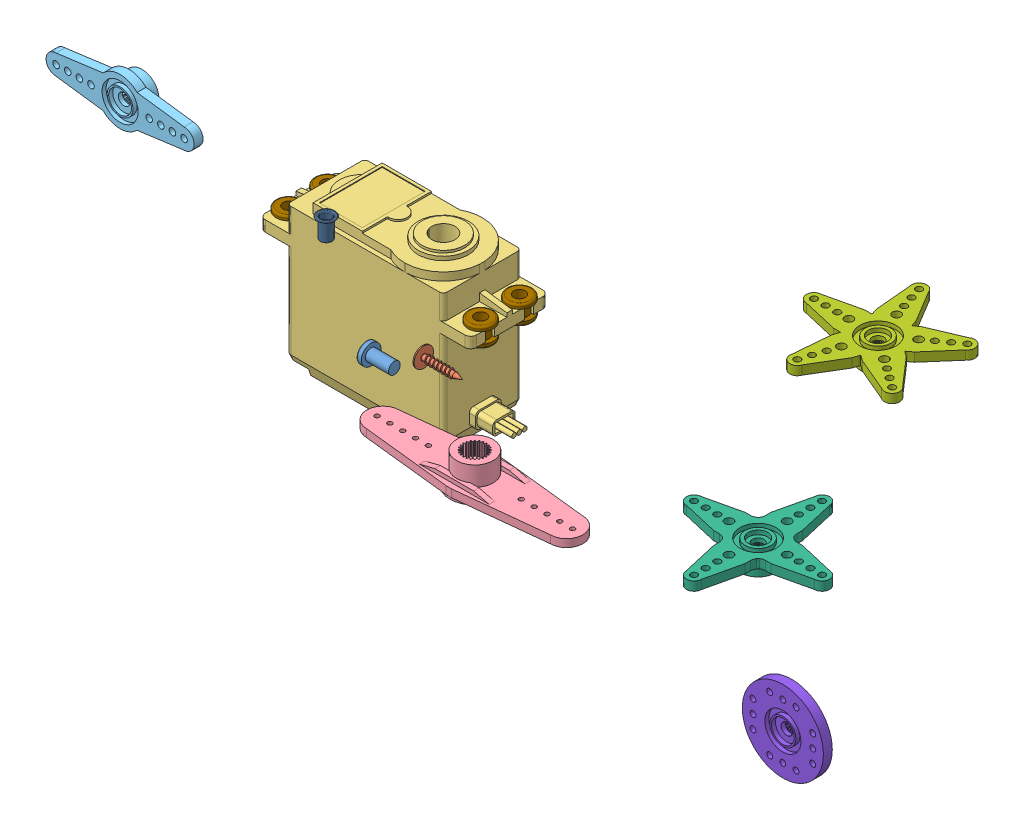
SolidWorks assembly Montaj2, configuration Varsayılan. Lengths in mm.
Overall size (199.66 99.97 80.09).
13 component instances, 10 part files, 8 mates.
Components (placement in the parent):
- Parça10-1: Parça10 [Varsayılan] at (3.514 0.621 7.8011) size (7.8 5.1 5.1)
- parça11,-1: parça11, [ISO 7045 - M2 x 10 - Z --- 10N] at (8.0473 5.0799 6.0539) size (11.27 5 5)
- Parça2-1: Parça2 [Varsayılan] at (3.3747 1.6828 -33.4922) size (56.95 39.84 20.1)
- Parça3-1: Parça3 [Varsayılan] at (21.2964 -18.0731 4.8529) size (55.74 7.8 13.34)
- Parça4-1: Parça4 [Varsayılan] at (-73.4653 18.488 -4.0489) size (38.2 12.15 5.6)
- Parça5-1: Parça5 [Varsayılan] at (81.6763 -11.6361 -7.7899) size (36.89 5.6 36.89)
- Parça6-1: Parça6 [Varsayılan] at (91.8005 28.1917 -28.5862) size (33.74 5.6 35.28)
- Parça8-1: Parça8 [Varsayılan] at (94.383 -39.6825 -7.0758) size (20.9 20.9 5.6)
- parça9-1: parça9 [Varsayılan] at (-0.4912 -8.0155 -16.9611) size (6.5 5 6.5)
- part7-1: part7 [Défaut] at (9.7488 49.8418 31.6193) size (4.5 5.2 4.5)
- parça9-2: parça9 [Varsayılan] at (-1.5574 -8.0155 -27.4165) x (0.693077 0 0.720863) z (-0.720863 0 0.693077) size (6.5 5 6.5)
- parça9-3: parça9 [Varsayılan] at (-49.9735 -8.0155 -26.9541) size (6.5 5 6.5)
- parça9-4: parça9 [Varsayılan] at (-49.9811 -8.0155 -16.9659) size (6.5 5 6.5)
Mates (geometry in assembly coordinates):
- Eş Merkezli1: concentric aligned: cylinder of Parça2-1 through (-0.4912 -45.3155 -18.4411) axis (0 1 0) radius 2.13; cylinder of parça9-1 through (-0.4912 -3.0155 -18.4411) axis (0 1 0) radius 2.13
- Çakışık1: coincident anti-aligned: plane of Parça2-1 through (1.9654 -4.1155 -13.3922) normal (0 1 0); plane of parça9-1 through (-0.4912 -4.1155 -16.3111) normal (0 -1 0)
- Eş Merkezli2: concentric aligned: cylinder of Parça2-1 through (-0.4905 -45.3155 -28.4422) axis (0 1 0) radius 2.13; cylinder of parça9-2 through (-0.4905 -3.0155 -28.4422) axis (0 1 0) radius 2.13
- Çakışık2: coincident anti-aligned: plane of Parça2-1 through (1.9654 -4.1155 -13.3922) normal (0 1 0); plane of parça9-2 through (-2.0259 -4.1155 -26.966) normal (0 -1 0)
- Çakışık3: coincident anti-aligned: plane of Parça2-1 through (-52.4346 -4.1155 -13.3922) normal (0 1 0); plane of parça9-3 through (-49.9735 -4.1155 -26.3041) normal (0 -1 0)
- Eş Merkezli3: concentric aligned: cylinder of Parça2-1 through (-49.9735 -45.3155 -28.4341) axis (0 1 0) radius 2.13; cylinder of parça9-3 through (-49.9735 -3.0155 -28.4341) axis (0 1 0) radius 2.13
- Eş Merkezli4: concentric aligned: cylinder of Parça2-1 through (-49.9811 -45.3155 -18.4459) axis (0 1 0) radius 2.13; cylinder of parça9-4 through (-49.9811 -3.0155 -18.4459) axis (0 1 0) radius 2.13
- Çakışık4: coincident anti-aligned: plane of Parça2-1 through (-52.4346 -4.1155 -13.3922) normal (0 1 0); plane of parça9-4 through (-49.9811 -4.1155 -16.3159) normal (0 -1 0)
